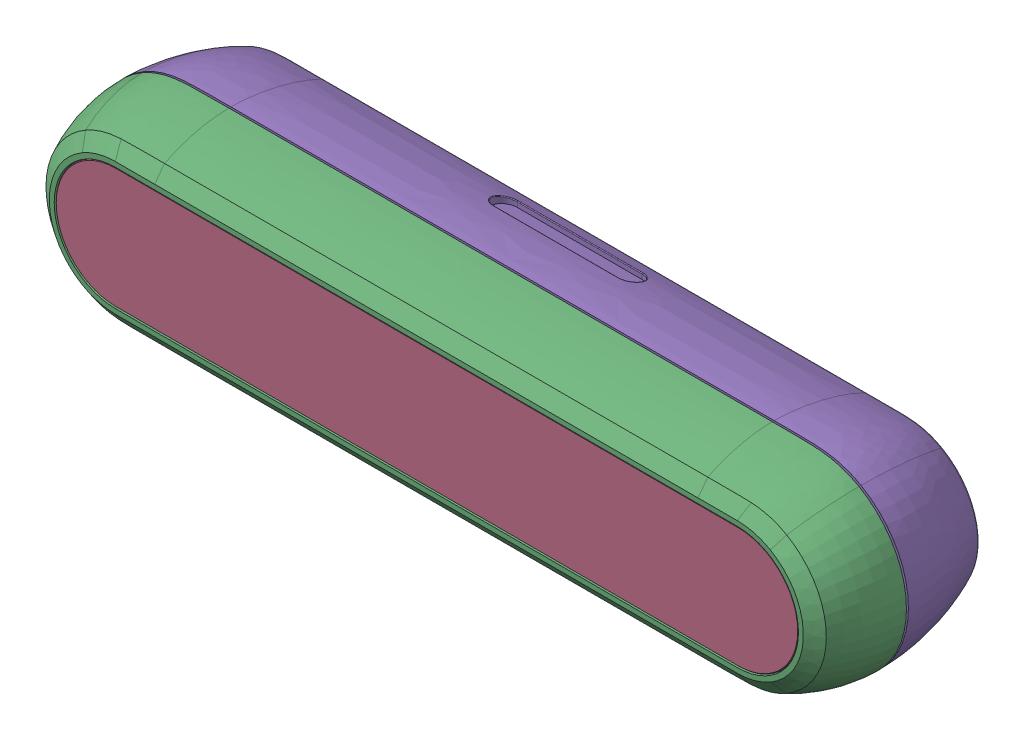
SolidWorks assembly MD0645501_ASM_12_ASM, configuration MD0645501_ASM_12_ASM. Lengths in mm.
Overall size (124.01 29.03 26.02).
38 component instances, 18 part files, 0 mates.
Components (placement in the parent):
- AM0600131_ASM_2_ASM-1: AM0600131_ASM_2_ASM [AM0600131_ASM_2_ASM] at origin size (124 29.01 12.31)
  - MEC060312_ASM_4_ASM-1: MEC060312_ASM_4_ASM [MEC060312_ASM_4_ASM] at origin size (111.1 18.8 0.79)
    - DS5_0390_FOAM_FRONT_D455_3-1: DS5_0390_FOAM_FRONT_D455_3 [DS5_0390_FOAM_FRONT_D455_3] at origin size (111.1 18.8 0.76)
    - DS5_0390_ADHESIVE_D455_2-1: DS5_0390_ADHESIVE_D455_2 [DS5_0390_ADHESIVE_D455_2] at (0 0 -1.32) size (111.1 18.8 0.03)
  - MEC060311_6-1: MEC060311_6 [MEC060311_6] at origin size (124 29.01 12.31)
- AM0600132_ASM_3_ASM-1: AM0600132_ASM_3_ASM [AM0600132_ASM_3_ASM] at origin size (113.48 18.48 0.7)
  - MEC060313_2-1: MEC060313_2 [MEC060313_2] at origin size (113.48 18.48 0.55)
  - MASK_LENS_COVER_D455_3-1: MASK_LENS_COVER_D455_3 [MASK_LENS_COVER_D455_3] at origin size (113.28 18.28 0.03)
  - MEC060314_5-1: MEC060314_5 [MEC060314_5] at origin size (112.88 17.88 0.13)
- AM0600135_ASM_3_ASM-1: AM0600135_ASM_3_ASM [AM0600135_ASM_3_ASM] at origin size (120.07 27.45 12.56)
  - MEC060318_11-1: MEC060318_11 [MEC060318_11] at origin size (120.07 27.45 12.56)
  - MEC060319_2-1: MEC060319_2 [MEC060319_2] at (35.3 0 -12.295) size (1.48 1.48 3)
  - MEC060319_2-2: MEC060319_2 [MEC060319_2] at (-38.5 0 -12.295) size (1.48 1.48 3)
- MEC060309_ASM_5_ASM-1: MEC060309_ASM_5_ASM [MEC060309_ASM_5_ASM] at origin size (108.7 16.4 1.68)
  - DS5_0390_LABEL_FRONT_MOD_D455_5-1: DS5_0390_LABEL_FRONT_MOD_D455_5 [DS5_0390_LABEL_FRONT_MOD_D455_5] at origin size (108.7 16.4 1.68)
  - DS5_0390_LABEL_FRONT_ADH_D455_3-1: DS5_0390_LABEL_FRONT_ADH_D455_3 [DS5_0390_LABEL_FRONT_ADH_D455_3] at origin size (108.7 16.4 0.06)
- AS0605401_ASM_4_ASM-1: AS0605401_ASM_4_ASM [AS0605401_ASM_4_ASM] at origin size (8.74 8.48 3.97)
  - 10137062C_1_ASM_2_ASM-1: 10137062C_1_ASM_2_ASM [10137062C_1_ASM_2_ASM] at (-37.01 -9 -21.3) x (1 0 0) z (0 -1 0) size (8.74 3.97 8.48)
    - 10137062C_1_1_1-1: 10137062C_1_1_1 [10137062C_1_1_1] at origin size (8.74 3.97 8.48)
- AM0600133_ASM_2_ASM-1: AM0600133_ASM_2_ASM [AM0600133_ASM_2_ASM] at origin size (124.01 29.03 14.45)
  - FAS000227_ASM_2_ASM-1: FAS000227_ASM_2_ASM [FAS000227_ASM_2_ASM] at (-47.5 0 -25.4937) x (-1 0 0) z (0 1 0) size (5.62 3.92 5.68)
    - 91732A649_ASM_1_ASM-1: 91732A649_ASM_1_ASM [91732A649_ASM_1_ASM] at origin size (5.62 3.92 5.68)
      - SWEEP1_1-1: SWEEP1_1 [SWEEP1_1] at origin size (5.62 3.92 5.68)
  - FAS000227_ASM_2_ASM-2: FAS000227_ASM_2_ASM [FAS000227_ASM_2_ASM] at (47.5 0 -25.4937) x (-1 0 0) z (0 1 0) size (5.62 3.92 5.68)
    - 91732A649_ASM_1_ASM-1: 91732A649_ASM_1_ASM [91732A649_ASM_1_ASM] at origin size (5.62 3.92 5.68)
      - SWEEP1_1-1: SWEEP1_1 [SWEEP1_1] at origin size (5.62 3.92 5.68)
  - FAS000226_ASM_2_ASM-1: FAS000226_ASM_2_ASM [FAS000226_ASM_2_ASM] at (-44.51 -14.325 -19.85) size (2.7 1.95 2.7)
    - 91732A181_ASM_1_ASM-1: 91732A181_ASM_1_ASM [91732A181_ASM_1_ASM] at origin size (2.7 1.95 2.7)
      - SWEEP1_1_2_3_1-1: SWEEP1_1_2_3_1 [SWEEP1_1_2_3_1] at origin size (2.7 1.95 2.7)
  - FAS000226_ASM_2_ASM-2: FAS000226_ASM_2_ASM [FAS000226_ASM_2_ASM] at (-29.51 -14.325 -19.85) size (2.7 1.95 2.7)
    - 91732A181_ASM_1_ASM-1: 91732A181_ASM_1_ASM [91732A181_ASM_1_ASM] at origin size (2.7 1.95 2.7)
      - SWEEP1_1_2_3_1-1: SWEEP1_1_2_3_1 [SWEEP1_1_2_3_1] at origin size (2.7 1.95 2.7)
  - MEC060316_8-1: MEC060316_8 [MEC060316_8] at origin size (124.01 29.03 14.45)
  - MEC060019_1-1: MEC060019_1 [MEC060019_1] at (-2.4 9.5 -21.62) x (-1 0 0) z (0 1 0) size (1.6 1.6 1.6)
- MEC060304_3-1: MEC060304_3 [MEC060304_3] at origin size (107.7 15.4 0.38)
- FAS000225_6-1: FAS000225_6 [FAS000225_6] at (-58.25 0 -10.07) size (3.2 3.2 5.1)
- FAS000225_6-2: FAS000225_6 [FAS000225_6] at (58.25 0 -10.07) size (3.2 3.2 5.1)
- MEC060308_5-1: MEC060308_5 [MEC060308_5] at origin size (17.09 8.12 6.4)
